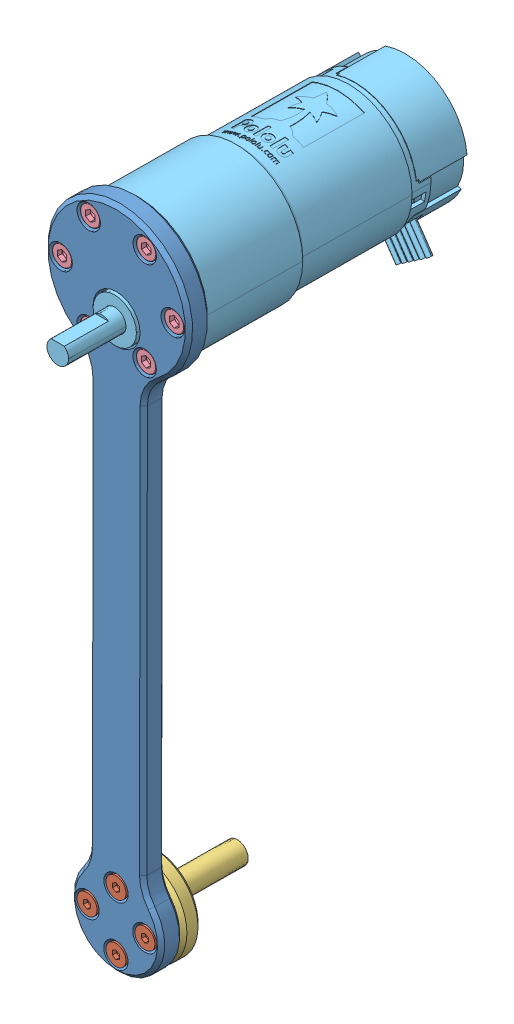
SolidWorks assembly Pendulum Assem, configuration Default. Lengths in mm.
Overall size (40.28 182.55 94.92).
13 component instances, 5 part files, 22 mates.
Components (placement in the parent):
- pendulum-1: pendulum [Default] at (12.3419 99.9999 36.7472) x (0.999961 -0.001272 0.008727) z (-0.008727 0 0.999962) size (40 182.5 6)
- socket countersunk head screw_iso-1: socket countersunk head screw_iso [ISO 10642 - M3 x 12 - 12N] at (12.1839 17 42.746) x (0.008727 0 -0.999962) z (0.999952 0.00442 0.008726) size (12 5.54 5.54)
- socket countersunk head screw_iso-2: socket countersunk head screw_iso [ISO 10642 - M3 x 12 - 12N] at (4.1944 25.0102 42.6763) x (0.008727 0 -0.999962) z (0.999918 0.00933 0.008726) size (12 5.54 5.54)
- socket countersunk head screw_iso-3: socket countersunk head screw_iso [ISO 10642 - M3 x 12 - 12N] at (20.1938 24.9898 42.8159) x (0.008727 0 -0.999962) z (0.999932 0.007779 0.008726) size (12 5.54 5.54)
- socket countersunk head screw_iso-4: socket countersunk head screw_iso [ISO 10642 - M3 x 12 - 12N] at (12.2043 33 42.7462) x (0.008727 0 -0.999962) z (0.999933 0.007608 0.008726) size (12 5.54 5.54)
- Shaft-1: Shaft [Default] at (12.2465 25 36.7463) x (0.999961 -0.001272 0.008727) z (-0.008727 0 0.999962) size (25 25 27)
- socket head cap screw_iso-1: socket head cap screw_iso [ISO 4762 M3 x 5 - 5N] at (4.6558 188.4331 42.2803) x (0.008727 0 -0.999962) z (0.999962 0 0.008727) size (8 5.5 5.5)
- socket head cap screw_iso-2: socket head cap screw_iso [ISO 4762 M3 x 5 - 5N] at (4.6216 161.5864 42.28) x (0.008727 0 -0.999962) z (0.999962 0 0.008727) size (8 5.5 5.5)
- socket head cap screw_iso-3: socket head cap screw_iso [ISO 4762 M3 x 5 - 5N] at (20.121 161.5666 42.4153) x (0.008727 0 -0.999962) z (0.999962 0 0.008727) size (8 5.5 5.5)
- socket head cap screw_iso-4: socket head cap screw_iso [ISO 4762 M3 x 5 - 5N] at (27.8878 174.9802 42.483) x (0.008727 0 -0.999962) z (0.999962 0 0.008727) size (8 5.5 5.5)
- socket head cap screw_iso-5: socket head cap screw_iso [ISO 4762 M3 x 5 - 5N] at (20.1552 188.4134 42.4156) x (0.008727 0 -0.999962) z (0.999962 0 0.008727) size (8 5.5 5.5)
- socket head cap screw_iso-6: socket head cap screw_iso [ISO 4762 M3 x 5 - 5N] at (-3.111 175.0196 42.2125) x (0.008727 0 -0.999962) z (0.999962 0 0.008727) size (8 5.5 5.5)
- 37d-gearmotor-100-131-150-encoder.step-1: 37d-gearmotor-100-131-150-encoder.step [Default] at (-7.3131 175.0252 16.6499) x (0.999961 -0.001272 0.008727) z (-0.008727 0 0.999962) size (36.88 41.23 94.6)
Mates (geometry in assembly coordinates):
- Concentric1: concentric aligned: cylinder of pendulum-1 through (20.1517 188.4134 42.8155) axis (-0.008727 0 0.999962) radius 1.7; cylinder of socket head cap screw_iso-5 through (19.8781 188.4134 74.1643) axis (-0.008727 0 0.999962) radius 2.75
- Coincident1: coincident anti-aligned: plane of pendulum-1 through (21.8813 188.4112 39.4305) normal (-0.008727 0 0.999962); plane of socket head cap screw_iso-5 through (20.1814 191.1634 39.4157) normal (0.008727 0 -0.999962)
- Concentric2: concentric aligned: cylinder of pendulum-1 through (27.8843 174.9802 42.883) axis (-0.008727 0 0.999962) radius 1.7; cylinder of socket head cap screw_iso-4 through (27.6107 174.9802 74.2318) axis (-0.008727 0 0.999962) radius 2.75
- Coincident2: coincident anti-aligned: plane of pendulum-1 through (29.6139 174.978 39.498) normal (-0.008727 0 0.999962); plane of socket head cap screw_iso-4 through (27.914 177.7302 39.4831) normal (0.008727 0 -0.999962)
- Concentric3: concentric aligned: cylinder of pendulum-1 through (20.1175 161.5666 42.8152) axis (-0.008727 0 0.999962) radius 1.7; cylinder of socket head cap screw_iso-3 through (19.844 161.5666 74.164) axis (-0.008727 0 0.999962) radius 2.75
- Coincident3: coincident anti-aligned: plane of pendulum-1 through (21.8471 161.5645 39.4302) normal (-0.008727 0 0.999962); plane of socket head cap screw_iso-3 through (20.1472 164.3166 39.4154) normal (0.008727 0 -0.999962)
- Concentric4: concentric aligned: cylinder of pendulum-1 through (4.6181 161.5864 42.68) axis (-0.008727 0 0.999962) radius 1.7; cylinder of socket head cap screw_iso-2 through (4.3446 161.5864 74.0288) axis (-0.008727 0 0.999962) radius 2.75
- Coincident4: coincident anti-aligned: plane of pendulum-1 through (6.3477 161.5842 39.2949) normal (-0.008727 0 0.999962); plane of socket head cap screw_iso-2 through (4.6478 164.3364 39.2801) normal (0.008727 0 -0.999962)
- Concentric5: concentric aligned: cylinder of pendulum-1 through (-3.1145 175.0196 42.6125) axis (-0.008727 0 0.999962) radius 1.7; cylinder of socket head cap screw_iso-6 through (-3.3881 175.0196 73.9613) axis (-0.008727 0 0.999962) radius 2.75
- Coincident5: coincident anti-aligned: plane of pendulum-1 through (-1.3849 175.0174 39.2275) normal (-0.008727 0 0.999962); plane of socket head cap screw_iso-6 through (-3.0848 177.7696 39.2126) normal (0.008727 0 -0.999962)
- Concentric6: concentric aligned: cylinder of pendulum-1 through (4.6523 188.4331 42.6803) axis (-0.008727 0 0.999962) radius 1.7; cylinder of socket head cap screw_iso-1 through (4.3787 188.4331 74.0291) axis (-0.008727 0 0.999962) radius 2.75
- Coincident6: coincident anti-aligned: plane of pendulum-1 through (6.3819 188.431 39.2952) normal (-0.008727 0 0.999962); plane of socket head cap screw_iso-1 through (4.682 191.1831 39.2804) normal (0.008727 0 -0.999962)
- Concentric11: concentric aligned: cylinder of pendulum-1 through (12.1941 25 42.7461) axis (0.008727 0 -0.999962) radius 12.5; cylinder of Shaft-1 through (12.4821 25 9.7473) axis (0.008727 0 -0.999962) radius 12.5
- Concentric12: concentric aligned: cylinder of pendulum-1 through (20.1938 24.9898 42.8159) axis (-0.008727 0 0.999962) radius 1.7; cylinder of Shaft-1 through (20.2461 24.9898 36.8161) axis (-0.008727 0 0.999962) radius 1.7
- Coincident10: coincident anti-aligned: plane of pendulum-1 through (12.3419 99.9999 36.7472) normal (0.008727 0 -0.999962); plane of Shaft-1 through (12.2465 25 36.7463) normal (-0.008727 0 0.999962)
- Coincident11: coincident aligned: cone of pendulum-1 through (12.2043 33 42.7462) axis (0.008727 0 -0.999962); cone of socket countersunk head screw_iso-4 through (12.2094 33 42.1562) axis (0.008727 0 -0.999962)
- Coincident12: coincident aligned: cone of pendulum-1 through (20.1938 24.9898 42.8159) axis (0.008727 0 -0.999962); cone of socket countersunk head screw_iso-3 through (20.1989 24.9898 42.2259) axis (0.008727 0 -0.999962)
- Coincident13: coincident aligned: cone of pendulum-1 through (4.1944 25.0102 42.6763) axis (0.008727 0 -0.999962); cone of socket countersunk head screw_iso-2 through (4.1996 25.0102 42.0863) axis (0.008727 0 -0.999962)
- Coincident14: coincident aligned: cone of pendulum-1 through (12.1839 17 42.746) axis (0.008727 0 -0.999962); cone of socket countersunk head screw_iso-1 through (12.1891 17 42.156) axis (0.008727 0 -0.999962)
- Concentric13: concentric anti-aligned: cylinder of pendulum-1 through (12.5888 167.9999 18.3638) axis (-0.008727 0 0.999962) radius 6.5; cylinder of 37d-gearmotor-100-131-150-encoder.step-1 through (12.3716 167.9999 43.2477) axis (0.008727 0 -0.999962) radius 6
- Coincident15: coincident anti-aligned: plane of pendulum-1 through (12.3419 99.9999 36.7472) normal (0.008727 0 -0.999962); plane of 37d-gearmotor-100-131-150-encoder.step-1 through (12.4373 174.9999 36.748) normal (-0.008727 0 0.999962)
- Concentric15: concentric aligned: cylinder of pendulum-1 through (20.1517 188.4134 42.8155) axis (-0.008727 0 0.999962) radius 3.25; cylinder of socket head cap screw_iso-5 through (19.8781 188.4134 74.1643) axis (-0.008727 0 0.999962) radius 1.5
